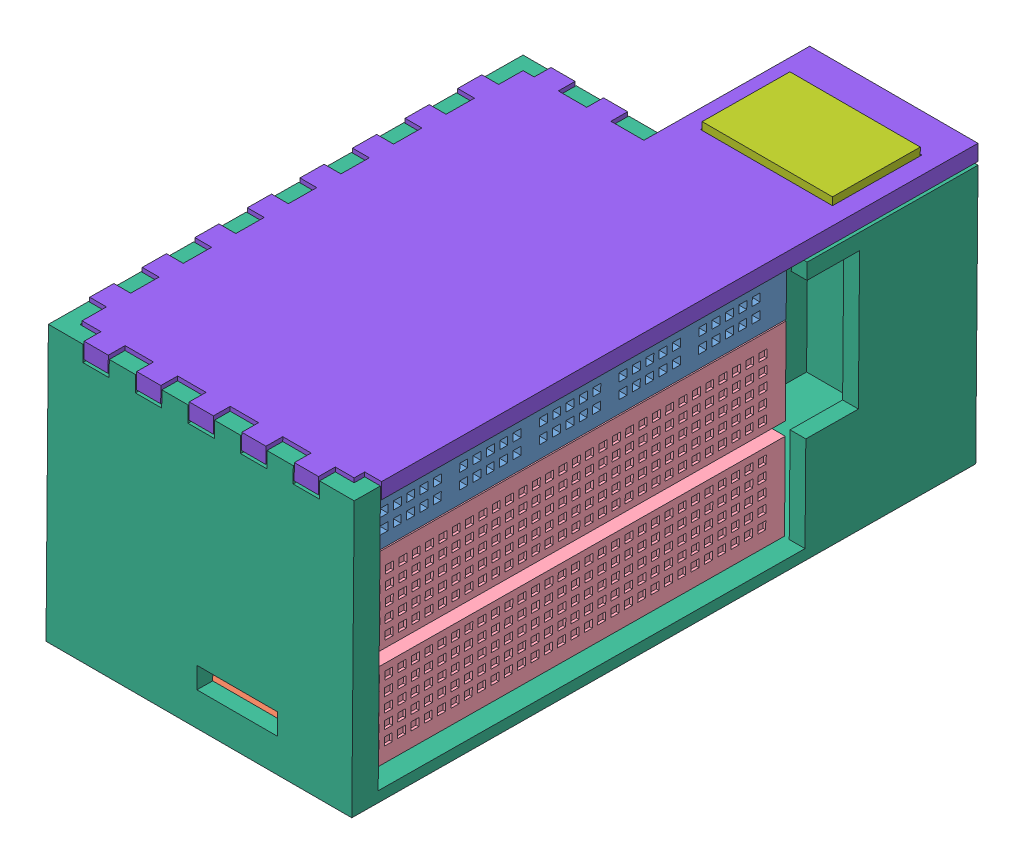
SolidWorks assembly Assem1, configuration Default. Lengths in mm.
Overall size (58.17 54.04 119.15).
9 component instances, 9 part files, 18 mates.
Components (placement in the parent):
- Breadboard_Mini_Powerline-2: Breadboard_Mini_Powerline [Default] at (25.5273 93.3265 71.7404) x (0 -0.999962 0.008727) z (0 0.008727 0.999962) size (11 9.2 84.1)
- RelayBoard-1: RelayBoard [Default] at (22.1173 56.2866 85.7234) x (0 -0.008727 -0.999962) z (1 0 0) size (69.9 18 22)
- AirQualitySensor-1: AirQualitySensor [Default] at (22.9873 83.6448 46.4529) x (0 0.026177 0.999657) z (0 -0.999657 0.026177) size (42.35 11.1 23.8)
- Breadboard_Mini-3: Breadboard_Mini [Default] at (25.5273 67.2004 38.1646) x (0 -0.999962 0.008727) z (0 0.008727 0.999962) size (37.1 9.2 84.1)
- DustSensor-1: DustSensor [Default] at (3.5073 81.2016 69.0292) x (0 0.008727 0.999962) z (0 -0.999962 0.008727) size (58.9 18.5 44.5)
- Part1^FulAssembly-1: Part1^FulAssembly [Default] at origin (virtual)
- Box-1: Box [Default] at (6.3971 53.2143 78.5989) x (0 -0.008727 -0.999962) z (1 0 0) size (118.7 52 58.17)
- OLED-2: OLED [Default] at (25.1121 103.2777 16.8812) x (-1 0 0) z (0 -0.008727 -0.999962) size (26 4 25.3)
- BoxLid-1: BoxLid [Default] at (19.6576 102.8576 82.5697) x (0 -0.008727 -0.999962) z (1 0 0) size (118.67 3 58.17)
Mates (geometry in assembly coordinates):
- Distance4: distance = 0.254 mm anti-aligned: plane of Breadboard_Mini-3 through (34.7273 90.0784 28.4763) normal (0 0.999962 -0.008727); plane of Breadboard_Mini_Powerline-2 through (34.7273 90.3323 28.4741) normal (0 -0.999962 0.008727)
- Coincident12: coincident aligned: plane of Breadboard_Mini_Powerline-2 through (34.7273 93.3265 71.7404) normal (1 0 0); plane of Breadboard_Mini-3 through (34.7273 67.2004 38.1646) normal (1 0 0)
- Coincident13: coincident aligned: plane of Breadboard_Mini_Powerline-2 through (34.7273 99.532 28.3938) normal (0 -0.008727 -0.999962); plane of Breadboard_Mini-3 through (34.7273 90.0784 28.4763) normal (0 -0.008727 -0.999962)
- Coincident19: coincident aligned: plane of Breadboard_Mini-3 through (34.7273 54.7797 28.7844) normal (0 -0.999962 0.008727); plane of DustSensor-1 through (1.9073 54.9839 52.1835) normal (0 -0.999962 0.008727)
- Coincident20: coincident aligned: plane of Breadboard_Mini-3 through (34.7273 90.7965 110.7732) normal (0 0.008727 0.999962); plane of DustSensor-1 through (1.9073 99.9962 110.6929) normal (0 0.008727 0.999962)
- Distance9: distance = 2.54 mm anti-aligned: plane of AirQualitySensor-1 through (22.9873 81.2197 31.9148) normal (1 0 0); plane of Breadboard_Mini-3 through (25.5273 67.2004 38.1646) normal (-1 0 0)
- Coincident23: coincident anti-aligned: plane of Breadboard_Mini-3 through (34.7273 54.7797 28.7844) normal (0 -0.999962 0.008727); plane of Box-1 through (6.3971 55.2143 78.5815) normal (0 0.999962 -0.008727)
- Distance11: distance = 4 mm aligned: plane of Box-1 through (38.7273 55.5328 115.0811) normal (1 0 0); plane of Breadboard_Mini-3 through (34.7273 67.2004 38.1646) normal (1 0 0)
- Distance12: distance = 4 mm aligned: plane of Box-1 through (-19.4427 55.5328 115.0811) normal (0 0.008727 0.999962); plane of Breadboard_Mini-3 through (34.7273 90.7965 110.7732) normal (0 0.008727 0.999962)
- Distance13: distance = 0.01 mm anti-aligned: plane of RelayBoard-1 through (25.5173 58.0078 111.0593) normal (1 0 0); plane of Breadboard_Mini-3 through (25.5273 67.2004 38.1646) normal (-1 0 0)
- Distance14: distance = 0.01 mm anti-aligned: plane of DustSensor-1 through (3.5073 81.2016 69.0292) normal (1 0 0); plane of RelayBoard-1 through (3.5173 58.0078 111.0593) normal (-1 0 0)
- Distance15: distance = 0.01 mm anti-aligned: plane of RelayBoard-1 through (22.1173 55.2867 85.7321) normal (0 -0.999962 0.008727); plane of Box-1 through (6.3971 55.2143 78.5815) normal (0 0.999962 -0.008727)
- Coincident30: coincident aligned: plane of RelayBoard-1 through (3.5173 58.0078 111.0593) normal (0 0.008727 0.999962); plane of Breadboard_Mini-3 through (34.7273 90.7965 110.7732) normal (0 0.008727 0.999962)
- Distance16: distance = 0.1 mm aligned: plane of OLED-2 through (25.1121 104.7776 16.8681) normal (0 0.999962 -0.008727); plane of Box-1 through (6.3971 105.2124 78.1452) normal (0 0.999962 -0.008727)
- Distance17: distance = 0.01 mm anti-aligned: plane of OLED-2 through (35.7173 104.6213 -1.0417) normal (0 -0.008727 -0.999962); plane of Box-1 through (35.7273 74.5224 -0.789) normal (0 0.008727 0.999962)
- Distance18: distance = 0.01 mm anti-aligned: plane of OLED-2 through (35.7173 104.8421 24.2573) normal (1 0 0); plane of Box-1 through (35.7273 74.7798 28.7098) normal (-1 0 0)
- Coincident35: coincident aligned: plane of Box-1 through (-19.4427 55.5328 115.0811) normal (0 0.008727 0.999962); plane of BoxLid-1 through (-12.6527 106.1375 114.6395) normal (0 0.008727 0.999962)
- Distance21: distance = 0.2 mm anti-aligned: plane of Box-1 through (-16.4427 74.9853 52.2527) normal (1 0 0); plane of BoxLid-1 through (-16.2427 106.1096 111.4396) normal (-1 0 0)
